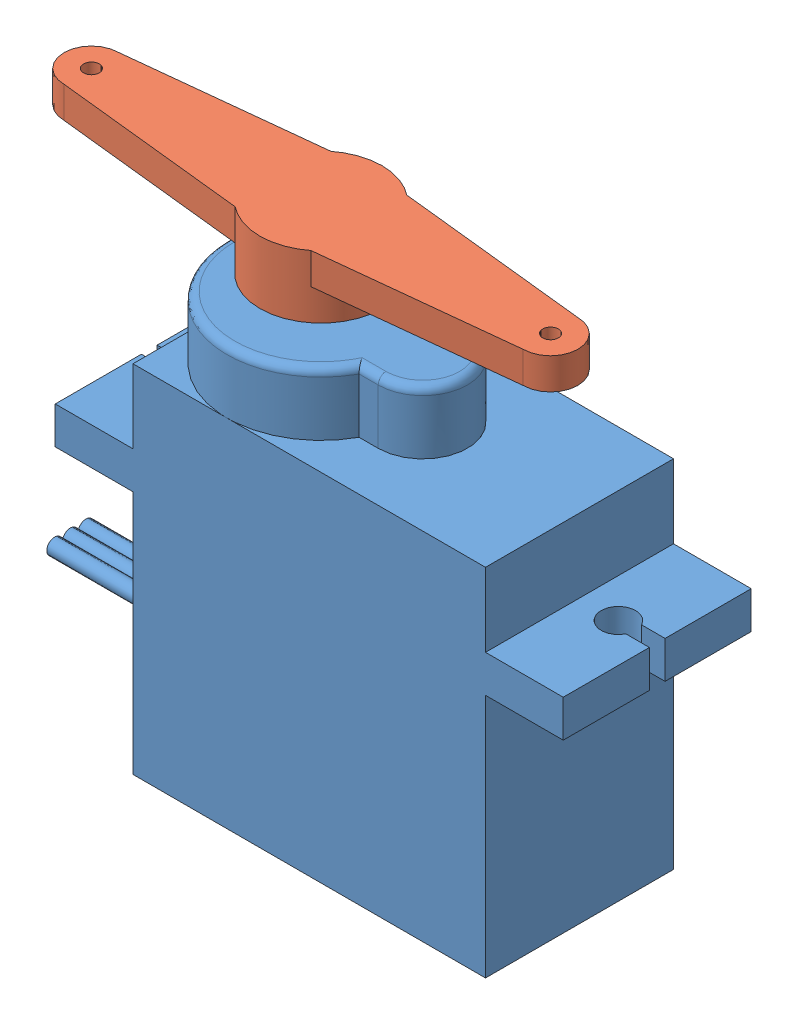
SolidWorks assembly Servo Assembly, configuration Default. Lengths in mm.
Overall size (37.86 31.7 12).
2 component instances, 2 part files, 2 mates.
Components (placement in the parent):
- Servo Body-1: Servo Body [Valor predeterminado] at origin size (37.46 29.7 12)
- Servo Horn-1: Servo Horn [Default] at (0.4566 11.7 -37.4292) size (32.8 4 7.8)
Mates (geometry in assembly coordinates):
- Coincident1: coincident: plane of assembly; plane of assembly; plane of Servo Body-1 through (-5.25 11.7 0) normal (0 1 0); plane of Servo Horn-1 through (-5.25 11.7 0) normal (0 -1 0)
- Concentric1: concentric: cylinder of assembly; cylinder of assembly; cylinder of Servo Body-1 through (-5.25 11.7 0) axis (0 -1 0) radius 2.25; cylinder of Servo Horn-1 through (-5.25 9.7 0) axis (0 1 0) radius 2.25
